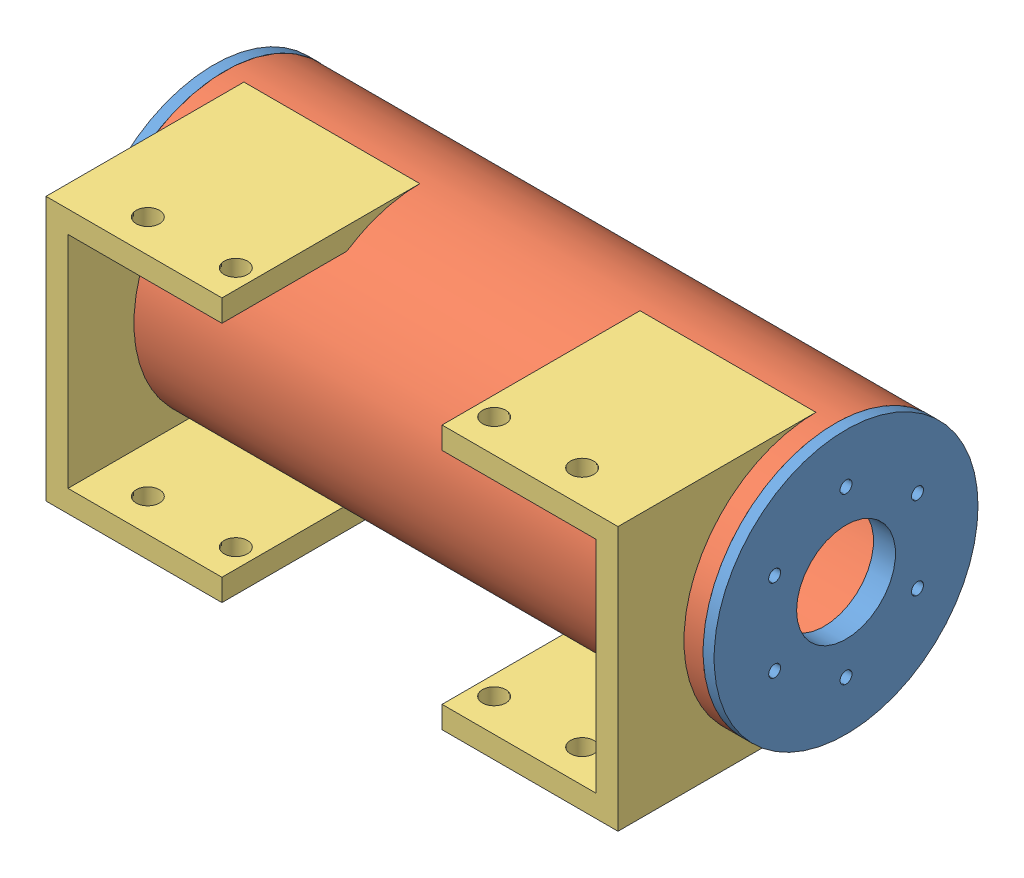
SolidWorks assembly 2018-303-A, configuration Default. Lengths in mm.
Overall size (182.56 91.95 103.13).
5 component instances, 3 part files, 11 mates.
Components (placement in the parent):
- 2018-303-D005-1: 2018-303-D005 [Default] at (9.1822 41.6905 65.6706) size (6.35 76.2 76.2)
- 2018-303-D002-1: 2018-303-D002 [Default] at (100.4634 41.6905 65.6706) x (1 0 0) z (0 0.972075 -0.234672) size (176.21 76.2 76.2)
- 2018-303-D005-2: 2018-303-D005 [Default] at (191.7447 41.6905 65.6706) x (-1 0 0) z (0 0 -1) size (6.35 76.2 76.2)
- 2018-303-D004-1: 2018-303-D004 [Default] at (17.8817 3.5905 65.6706) size (50.8 76.2 57.15)
- 2018-303-D004-2: 2018-303-D004 [Default] at (183.0452 79.7905 65.6706) x (-1 0 0) z (0 0 1) size (50.8 76.2 57.15)
Mates (geometry in assembly coordinates):
- Concentric1: concentric anti-aligned: cylinder of 2018-303-D005-1 through (12.3572 41.6905 65.6706) axis (1 0 0) radius 34.8488; cylinder of 2018-303-D002-1 through (188.5697 41.6905 65.6706) axis (-1 0 0) radius 34.925
- Coincident1: coincident anti-aligned: plane of 2018-303-D005-1 through (12.3572 41.6905 65.6706) normal (1 0 0); plane of 2018-303-D002-1 through (12.3572 41.6905 65.6706) normal (-1 0 0)
- Concentric2: concentric aligned: cylinder of 2018-303-D002-1 through (188.5697 41.6905 65.6706) axis (-1 0 0) radius 34.925; cylinder of 2018-303-D005-2 through (188.5697 41.6905 65.6706) axis (-1 0 0) radius 34.8488
- Coincident2: coincident anti-aligned: plane of 2018-303-D002-1 through (188.5697 41.6905 65.6706) normal (1 0 0); plane of 2018-303-D005-2 through (188.5697 41.6905 65.6706) normal (-1 0 0)
- Coincident3: coincident anti-aligned: plane of 2018-303-D005-1 through (9.1822 41.6905 65.6706) normal (0 0 1); plane of 2018-303-D005-2 through (191.7447 41.6905 65.6706) normal (0 0 -1)
- Concentric4: concentric anti-aligned: cylinder of 2018-303-D002-1 through (188.5697 41.6905 65.6706) axis (-1 0 0) radius 38.1; cylinder of 2018-303-D004-1 through (17.888 41.6905 65.6706) axis (1 0 0) radius 38.1
- Parallel1: parallel aligned: plane of 2018-303-D004-1 through (17.888 79.7905 122.8206) normal (0 1 0); plane of assembly through (0 0 0) normal (0 1 0)
- Concentric5: concentric aligned: cylinder of 2018-303-D002-1 through (188.5697 41.6905 65.6706) axis (-1 0 0) radius 38.1; cylinder of 2018-303-D004-2 through (183.0388 41.6905 65.6706) axis (-1 0 0) radius 38.1
- Parallel2: parallel aligned: plane of 2018-303-D004-1 through (17.888 79.7905 122.8206) normal (0 1 0); plane of 2018-303-D004-2 through (183.0388 79.7905 122.8206) normal (0 1 0)
- Width1: width anti-aligned: plane of 2018-303-D005-1 through (9.1822 41.6905 65.6706) normal (-1 0 0); plane of 2018-303-D005-2 through (191.7447 41.6905 65.6706) normal (1 0 0); plane of 2018-303-D004-2 through (183.0388 79.7905 122.8206) normal (1 0 0); plane of 2018-303-D004-1 through (17.888 3.5905 122.8206) normal (-1 0 0)
- Distance1: distance = 118.6434 mm: cylinder of 2018-303-D004-1 through (37.7635 79.7905 113.2956) axis (0 1 0) radius 3.3782; cylinder of 2018-303-D004-2 through (163.1633 3.5905 113.2956) axis (0 -1 0) radius 3.3782
